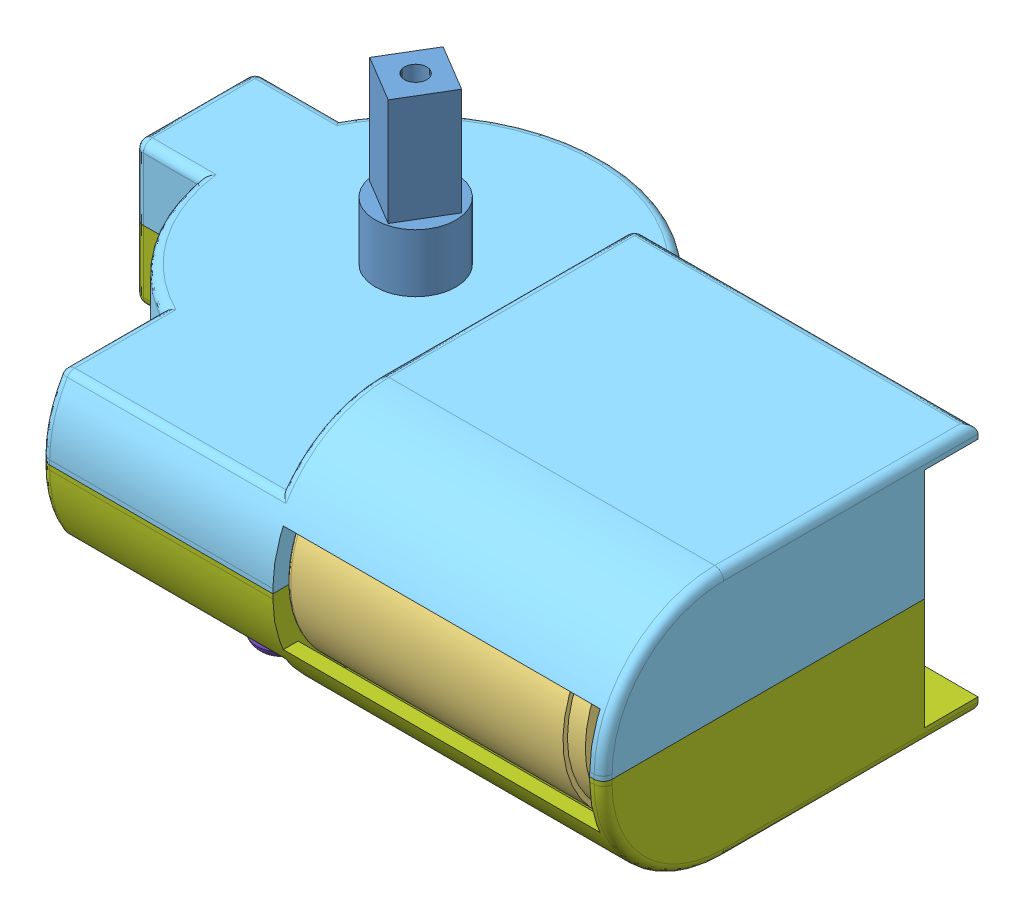
SolidWorks assembly Motor (right), configuration Default. Lengths in mm.
Overall size (81 42.94 53.52).
15 component instances, 8 part files, 0 mates.
Components (placement in the parent):
- Motor (right).step-1: Motor (right).step [Default] at origin size (81 42.94 53.52)
  - Drivning_sub_assembly_hoger_ojaobz-5.step-1: Drivning_sub_assembly_hoger_ojaobz-5.step [Default] at (-111.5904 88.75 -39.0933) x (0 0 1) z (0 -1 0) size (53.52 81 42.94)
    - Planetbararaxel_ojaobz-5.step-1: Planetbararaxel_ojaobz-5.step [Default] at (58.5933 -144.5892 9.5) x (0.858335 0.513089 0) z (0 0 -1) size (20 20 26)
    - Planethjul_ojaobz-5.step-1: Planethjul_ojaobz-5.step [Default] at (66.1361 -146.488 9.5) x (0.473276 -0.880914 0) z (0 0 1) size (8.23 8.46 4)
    - Planethjul_ojaobz-5.step-2: Planethjul_ojaobz-5.step [Default] at (60.4922 -137.0463 13.5) x (0.983504 0.180887 0) z (0 0 -1) size (8.23 8.46 4)
    - Planethjul_ojaobz-5.step-3: Planethjul_ojaobz-5.step [Default] at (51.0505 -142.6903 13.5) x (0.900482 -0.434894 0) z (0 0 -1) size (8.23 8.46 4)
    - Planethjul_ojaobz-5.step-4: Planethjul_ojaobz-5.step [Default] at (56.6945 -152.132 13.5) x (0.983391 0.181501 0) z (0 0 -1) size (8.23 8.46 4)
    - Motor_drivning_ojaobz-5.step-1: Motor_drivning_ojaobz-5.step [Default] at (77.0933 -191.5892 13.5) x (0 0 1) z (0 1 0) size (24 32.5 40)
    - Snackskruv_drivning_ojaobz-5.step-1: Snackskruv_drivning_ojaobz-5.step [Default] at (77.0933 -159.0892 13.5) x (-0.064264 0 -0.997933) z (0 1 0) size (7.5 7.5 20.7)
    - Drivkapa_B_hoger_ojaobz-5.step-1: Drivkapa_B_hoger_ojaobz-5.step [Default] at (90.5933 -197.5892 0) size (53 81 20.5)
    - Snackhjul_drivning_ojaobz-5.step-1: Snackhjul_drivning_ojaobz-5.step [Default] at (58.5933 -144.5892 16.5) x (-0.946984 -0.32128 0) z (0 0 -1) size (33.93 33.93 10)
    - Drivkapa_A_hoger_ojaobz-5.step-1: Drivkapa_A_hoger_ojaobz-5.step [Default] at (90.5933 -197.5892 28) x (-1 0 0) z (0 0 -1) size (53 81 14)
    - Skruv_blank_10_ojaobz-5.step-1: Skruv_blank_10_ojaobz-5.step [Default] at (84.5933 -155.5892 22) x (-1 0 0) z (0 0 -1) size (5.6 5.6 11.94)
    - Skruv_blank_10_ojaobz-5.step-2: Skruv_blank_10_ojaobz-5.step [Default] at (55.3433 -122.5892 22) x (0 1 0) z (0 0 -1) size (5.6 5.6 11.94)
    - Skruv_blank_10_ojaobz-5.step-3: Skruv_blank_10_ojaobz-5.step [Default] at (61.5933 -177.5892 28) x (1 0 0) z (0 0 -1) size (5.6 5.6 11.94)
